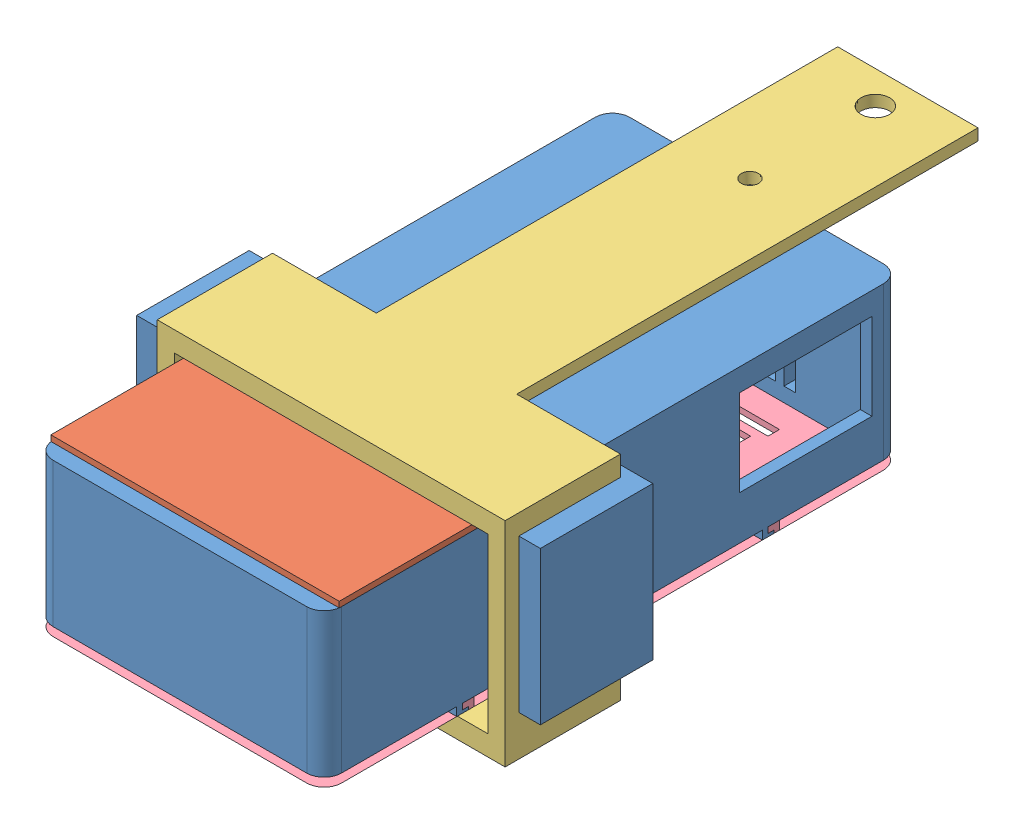
SolidWorks assembly Assem2, configuration Default. Lengths in mm.
Overall size (70 42.5 125.12).
4 component instances, 4 part files, 5 mates.
Components (placement in the parent):
- last_box_-1: last_box_ [Default] at (20.5518 -111.582 38.483) x (0 0 1) z (-1 0 0) size (100 28 70)
- pi1-1: pi1 [Default] at (20.5518 -86.582 71.3607) size (50 1 34)
- anthima last final wall design-1: anthima last final wall design [Default] at (17.438 -83.582 6.8945) size (60.33 37 100)
- last_cover-1: last_cover [Default] at (20.5518 -113.082 38.4764) x (0 0 1) z (1 0 0) size (100.01 14 50.01)
Mates (geometry in assembly coordinates):
- Coincident2: coincident aligned: line of last_box_-1 through (45.5518 -86.582 85.483) axis (0 0 -1); line of pi1-1 through (45.5518 -86.582 85.8607) axis (0 0 -1)
- Coincident3: coincident anti-aligned: line of last_box_-1 through (-4.4482 -86.582 59.483) axis (0 0 1); line of pi1-1 through (-4.4482 -86.582 85.8607) axis (0 0 -1)
- Coincident4: coincident anti-aligned: plane of last_box_-1 through (-1.4482 -85.082 -8.517) normal (0 1 0); plane of anthima last final wall design-1 through (-5.5031 -85.082 63.3651) normal (0 -1 0)
- Coincident5: coincident aligned: line of last_box_-1 through (-4.4482 -111.582 -8.517) axis (0 0 1); line of last_cover-1 through (-4.4482 -111.582 9.4764) axis (0 0 1)
- Coincident6: coincident aligned: line of last_box_-1 through (45.5518 -111.582 11.483) axis (0 0 -1); line of last_cover-1 through (45.5518 -111.582 11.4764) axis (0 0 -1)
